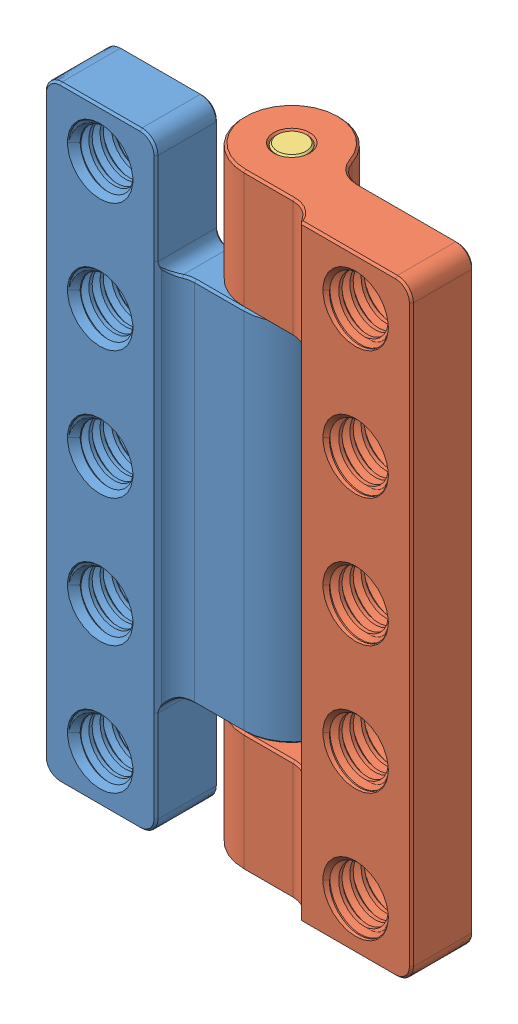
SolidWorks assembly 5 hole Hinge 2902-0005-0038, configuration Default. Lengths in mm.
Overall size (23 38 7).
3 component instances, 3 part files, 0 mates.
Components (placement in the parent):
- 2902-0005-0038 pt 2.STEP-1: 2902-0005-0038 pt 2.STEP [Default] at (-33.9362 -7.6908 11.82) size (14.5 38 7)
- 2902-0005-0038 pt 1.STEP-1: 2902-0005-0038 pt 1.STEP [Default] at (-33.9362 30.3092 11.82) x (-1 0 0) z (0 0 1) size (14.5 38 7)
- 2902-0005-0038 pt 3.STEP-1: 2902-0005-0038 pt 3.STEP [Default] at (-33.9362 -7.6908 11.82) size (2 38 2)
